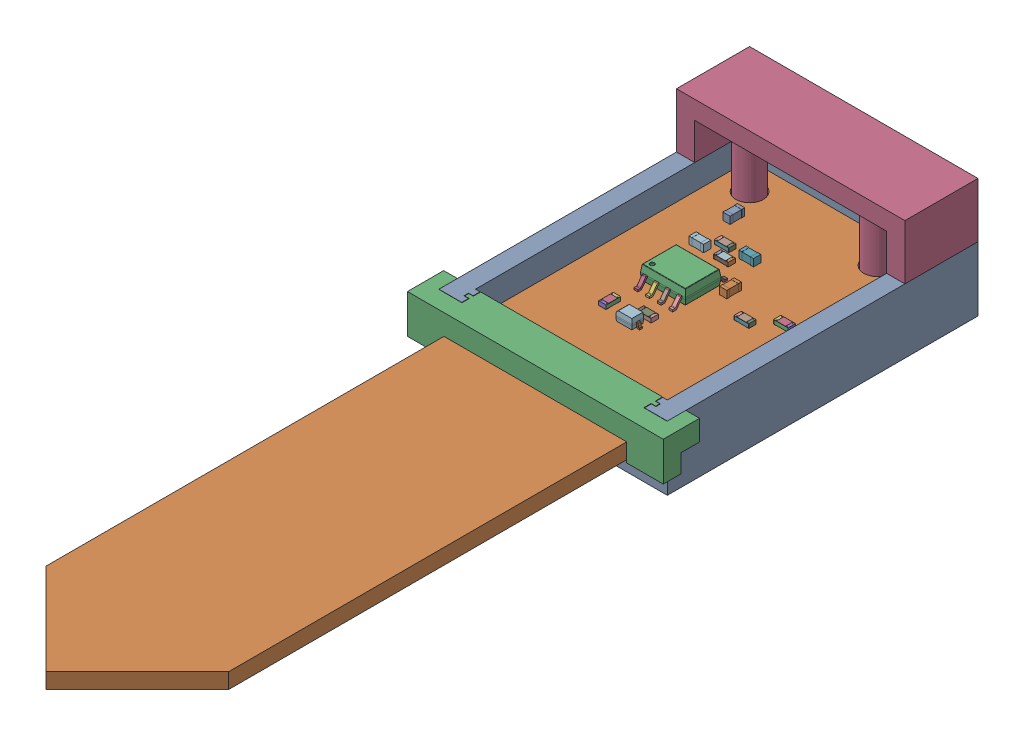
SolidWorks assembly KalıpMontaj, configuration Varsayılan. Lengths in mm.
Overall size (28 13.04 89.5).
4 component instances, 4 part files, 10 mates.
Components (placement in the parent):
- Kalıp1-1: Kalıp1 [Varsayılan] at (-1.3131 5.2762 3.8444) size (25 7.04 34)
- CSMST-1: CSMST [Varsayılan] at (-1.3131 10.0676 76.3444) x (1 0 0) z (0 1 0) size (20 87 4.24)
- Maça-1: Maça [Varsayılan] at (-1.3131 10.0676 22.8049) size (28 4.25 3.97)
- Maça2-1: Maça2 [Varsayılan] at (-1.3131 19.3562 3.8444) x (-1 0 0) z (0 0 1) size (25 11.54 8)
Mates (geometry in assembly coordinates):
- Çakışık1: coincident anti-aligned: plane of Kalıp1-1 through (8.6869 8.3762 20.8444) normal (0 1 0); plane of CSMST-1 through (-1.3131 8.3762 30.1203) normal (0 -1 0)
- Çakışık5: coincident anti-aligned: plane of CSMST-1 through (-1.3131 10.0676 30.1203) normal (0 1 0); plane of Maça-1 through (-1.3131 10.0676 22.8049) normal (0 -1 0)
- Genişlik1: width aligned: plane of Maça-1 through (-11.2631 12.3176 22.8049) normal (-1 0 0); plane of Kalıp1-1 through (8.6369 12.3176 22.8049) normal (1 0 0); plane of Maça-1 through (8.6869 12.3162 20.8444) normal (-1 0 0); plane of Kalıp1-1 through (-11.3131 8.3762 20.8444) normal (1 0 0)
- Genişlik2: width anti-aligned: plane of Maça-1 through (8.1369 12.3176 19.6194) normal (0 0 -1); plane of Kalıp1-1 through (8.1369 12.3176 20.0694) normal (0 0 1); plane of Maça-1 through (8.1869 10.3162 19.5944) normal (0 0 1); plane of Kalıp1-1 through (8.1869 10.3162 20.0944) normal (0 0 -1)
- Çakışık6: coincident aligned: plane of Kalıp1-1 through (-13.8131 5.2762 -13.1556) normal (-1 0 0); plane of Maça2-1 through (-13.8131 18.3162 -5.1556) normal (-1 0 0)
- Çakışık7: coincident anti-aligned: plane of Kalıp1-1 through (-1.3131 12.3162 3.8444) normal (0 1 0); plane of Maça2-1 through (-1.3131 12.3162 3.8444) normal (0 -1 0)
- Çakışık8: coincident aligned: plane of Kalıp1-1 through (11.1869 5.2762 -13.1556) normal (0 0 -1); plane of Maça2-1 through (11.1869 18.3162 -13.1556) normal (0 0 -1)
- Çakışık9: coincident anti-aligned: plane of Kalıp1-1 through (8.6869 8.3762 20.8444) normal (0 1 0); plane of CSMST-1 through (-1.3131 8.3762 30.1203) normal (0 -1 0)
- Eş Merkezli1: concentric aligned: circle of Kalıp1-1; circle of CSMST-1
- Eş Merkezli2: concentric aligned: circle of Kalıp1-1; circle of CSMST-1
